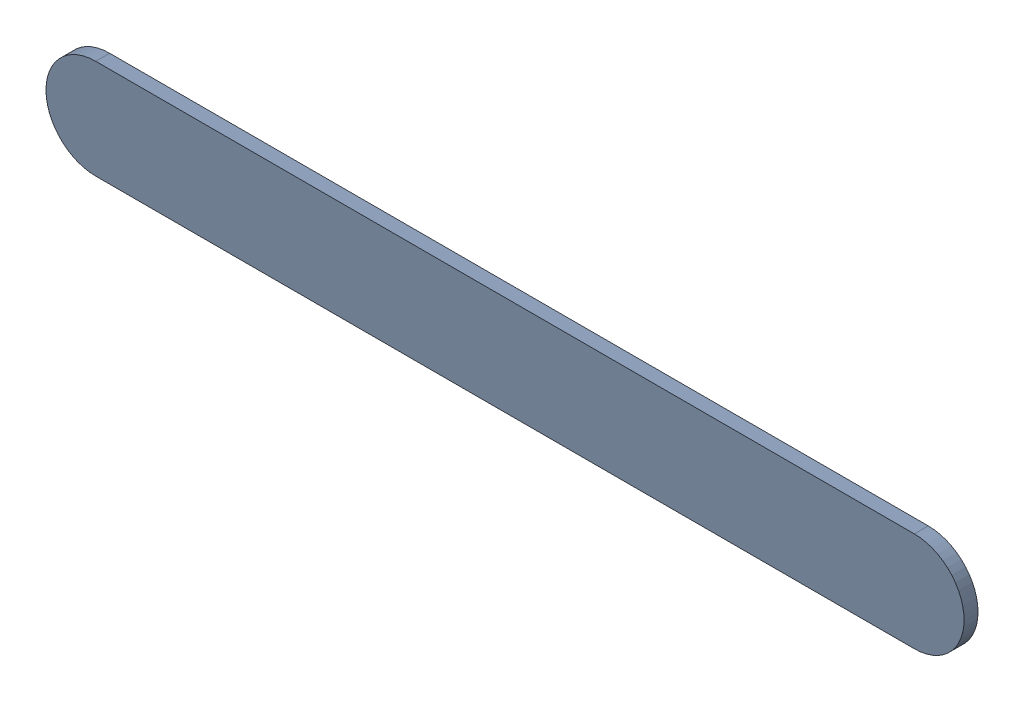
SolidWorks assembly Track (25.1mm,48.5mm)(27.19mm,48.5mm) on Top Layer, configuration Predeterminado. Lengths in mm.
Overall size (2.34 0.25 0.04).
2 component instances, 1 part files, 0 mates.
Components (placement in the parent):
- Track (25.1mm,48.5mm)(27.19mm,48.5mm) on Top Layer-1-1: Track (25.1mm,48.5mm)(27.19mm,48.5mm) on Top Layer-1 [Predeterminado] at (-68.317 -44.187 -0.0457) size (2.34 0.25 0.04)
  - Track (25.1mm,48.5mm)(27.19mm,48.5mm) on Top Layer-Part-1-1: Track (25.1mm,48.5mm)(27.19mm,48.5mm) on Top Layer-Part-1 [Predeterminado] at origin size (2.34 0.25 0.04)
